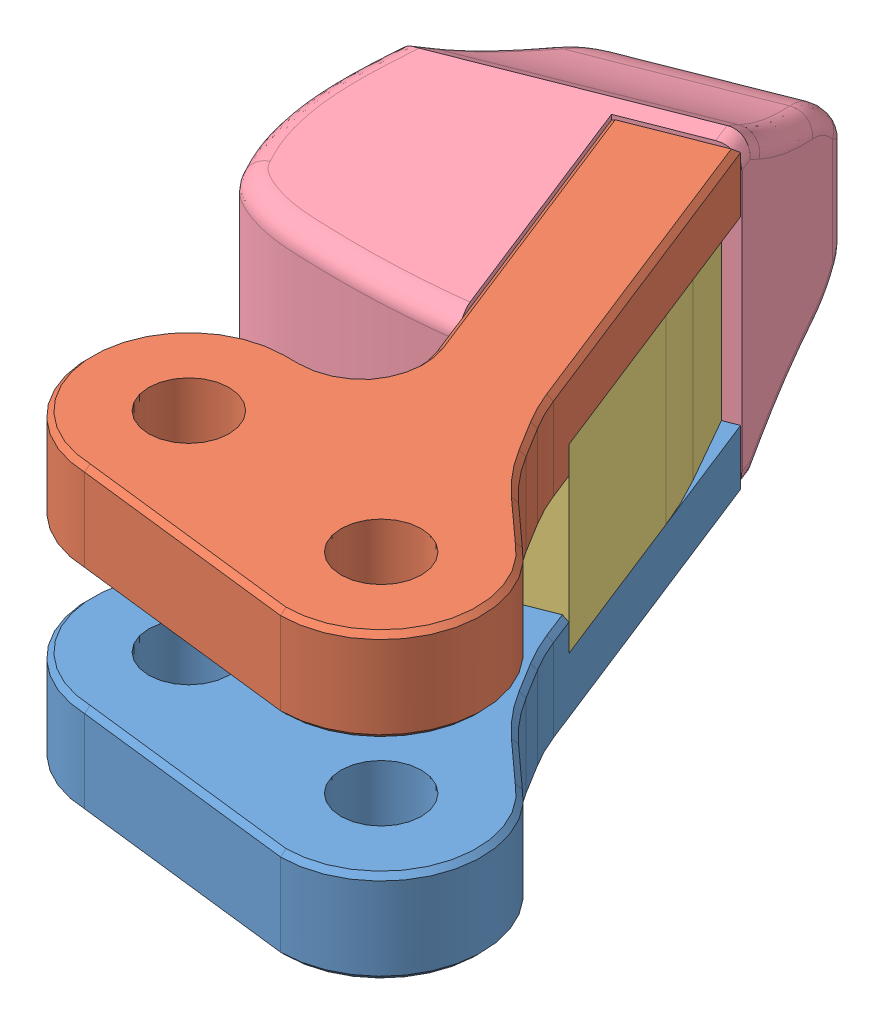
SolidWorks assembly plate6, configuration ﾃﾞﾌｫﾙﾄ. Lengths in mm.
Overall size (32.75 15.12 40.71).
4 component instances, 4 part files, 11 mates.
Components (placement in the parent):
- plate6_mirror-1: plate6_mirror [ﾃﾞﾌｫﾙﾄ] at (-80.5228 -2.6676 38.0895) size (20.87 4.6 31.39)
- plate6-1: plate6 [ﾃﾞﾌｫﾙﾄ] at (-80.5228 7.7324 38.0895) size (20.87 4.6 31.39)
- plate6_middle-1: plate6_middle [ﾃﾞﾌｫﾙﾄ] at (0.3895 0.3324 29.7922) x (0 1 0) z (0.36649 0 0.930422) size (9 10 24)
- plate6_rabbor-1: plate6_rabbor [ﾃﾞﾌｫﾙﾄ] at (-5.1219 12.3324 15.6772) x (-0.930422 0 0.36649) z (0.36649 0 0.930422) size (16.78 15.12 24.14)
Mates (geometry in assembly coordinates):
- 一致1: coincident anti-aligned: plane of plate6_mirror-1 through (-80.5228 0.3324 38.0895) normal (0 1 0); plane of plate6_middle-1 through (-17.7105 0.3324 11.1269) normal (0 -1 0)
- 一致2: coincident anti-aligned: plane of plate6-1 through (-80.5228 9.3324 38.0895) normal (0 -1 0); plane of plate6_middle-1 through (-8.9147 9.3324 33.4571) normal (0 1 0)
- 一致3: coincident anti-aligned: plane of plate6_mirror-1 through (-72.4844 0.3324 58.4969) normal (-0.36649 0 -0.930422); plane of plate6_middle-1 through (-8.9147 0.3324 33.4571) normal (0.36649 0 0.930422)
- 一致4: coincident aligned: plane of plate6-1 through (-7.6489 12.3324 9.3847) normal (0.930422 0 -0.36649); plane of plate6_middle-1 through (0.3895 0.3324 29.7922) normal (0.930422 0 -0.36649)
- 一致5: coincident aligned: plane of plate6_mirror-1 through (-7.6489 1.9324 9.3847) normal (0.930422 0 -0.36649); plane of plate6_middle-1 through (0.3895 0.3324 29.7922) normal (0.930422 0 -0.36649)
- 一致7: coincident anti-aligned: plane of plate6_mirror-1 through (-12.2591 1.9324 11.2007) normal (-0.930422 0 0.36649); plane of plate6_rabbor-1 through (-9.7741 -2.6676 17.5096) normal (0.930422 0 -0.36649)
- 一致9: coincident anti-aligned: plane of plate6-1 through (-12.2591 12.3324 11.2007) normal (-0.930422 0 0.36649); plane of plate6_rabbor-1 through (-9.7741 -2.6676 17.5096) normal (0.930422 0 -0.36649)
- 一致10: coincident aligned: plane of plate6_mirror-1 through (-80.5228 -2.6676 38.0895) normal (0 -1 0); plane of plate6_rabbor-1 through (-5.1219 -2.6676 15.6772) normal (0 -1 0)
- 一致11: coincident aligned: plane of plate6-1 through (-80.5228 12.3324 38.0895) normal (0 1 0); plane of plate6_rabbor-1 through (-5.1219 12.3324 15.6772) normal (0 1 0)
- 一致12: coincident anti-aligned: plane of plate6-1 through (-78.0377 12.3324 44.3985) normal (-0.36649 0 -0.930422); plane of plate6_rabbor-1 through (-5.1219 -2.6676 15.6772) normal (0.36649 0 0.930422)
- 一致13: coincident anti-aligned: plane of plate6_mirror-1 through (-78.0377 1.9324 44.3985) normal (-0.36649 0 -0.930422); plane of plate6_rabbor-1 through (-5.1219 -2.6676 15.6772) normal (0.36649 0 0.930422)
